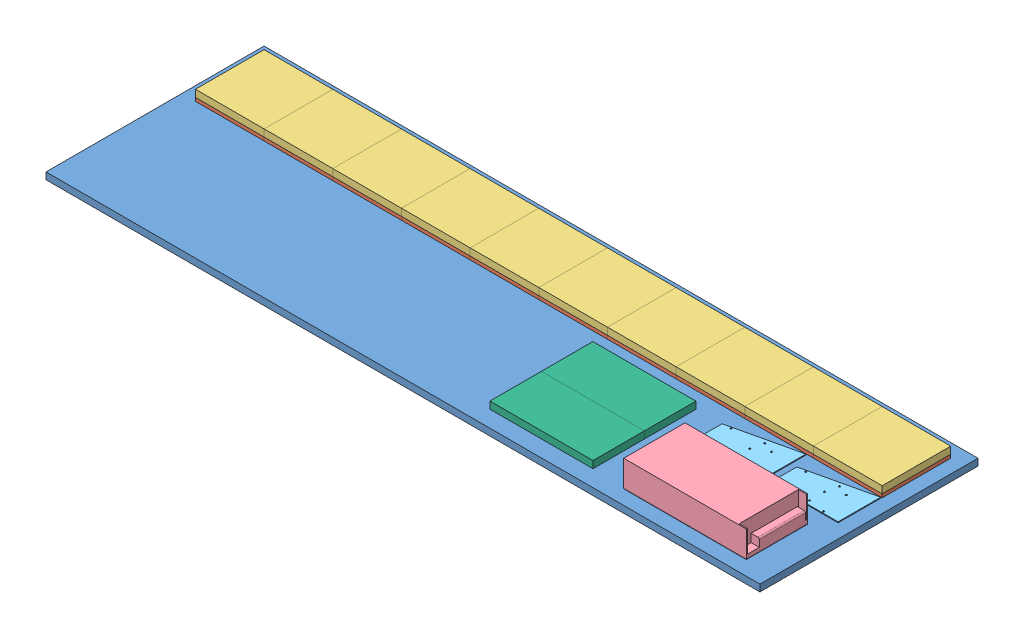
SolidWorks assembly Final_Assembly, configuration Default. Lengths in mm.
Overall size (1330.71 63.5 406.4).
28 component instances, 6 part files, 17 mates.
Components (placement in the parent):
- Back_Board-1: Back_Board [Default] at (-793.9979 16.0391 154.074) size (1330.71 12.7 406.4)
- 5_Display_Assembly-3: 5_Display_Assembly [Default] at (-36.1956 19.8584 -169.8312) size (639.95 19.53 127.84)
  - MDF-1: MDF [Default] at (-92.4493 8.8807 70.7434) size (127.99 6.35 127.84)
  - 32x32_Display-1: 32x32_Display [Default] at (-92.4493 15.2307 70.7434) size (127.99 16.87 127.84)
  - MDF-2: MDF [Default] at (35.5413 8.8807 70.7434) size (127.99 6.35 127.84)
  - MDF-3: MDF [Default] at (163.5319 8.8807 70.7434) size (127.99 6.35 127.84)
  - MDF-4: MDF [Default] at (291.5225 8.8807 70.7434) size (127.99 6.35 127.84)
  - MDF-5: MDF [Default] at (419.5131 8.8807 70.7434) size (127.99 6.35 127.84)
  - 32x32_Display-2: 32x32_Display [Default] at (35.5413 15.2307 70.7434) size (127.99 16.87 127.84)
  - 32x32_Display-3: 32x32_Display [Default] at (163.5319 15.2307 70.7434) size (127.99 16.87 127.84)
  - 32x32_Display-4: 32x32_Display [Default] at (291.5225 15.2307 70.7434) size (127.99 16.87 127.84)
  - 32x32_Display-5: 32x32_Display [Default] at (419.5131 15.2307 70.7434) size (127.99 16.87 127.84)
- 5_Display_Assembly-4: 5_Display_Assembly [Default] at (-676.1486 19.8584 -169.8312) size (639.95 19.53 127.84)
  - MDF-1: MDF [Default] at (-92.4493 8.8807 70.7434) size (127.99 6.35 127.84)
  - 32x32_Display-1: 32x32_Display [Default] at (-92.4493 15.2307 70.7434) size (127.99 16.87 127.84)
  - MDF-2: MDF [Default] at (35.5413 8.8807 70.7434) size (127.99 6.35 127.84)
  - MDF-3: MDF [Default] at (163.5319 8.8807 70.7434) size (127.99 6.35 127.84)
  - MDF-4: MDF [Default] at (291.5225 8.8807 70.7434) size (127.99 6.35 127.84)
  - MDF-5: MDF [Default] at (419.5131 8.8807 70.7434) size (127.99 6.35 127.84)
  - 32x32_Display-2: 32x32_Display [Default] at (35.5413 15.2307 70.7434) size (127.99 16.87 127.84)
  - 32x32_Display-3: 32x32_Display [Default] at (163.5319 15.2307 70.7434) size (127.99 16.87 127.84)
  - 32x32_Display-4: 32x32_Display [Default] at (291.5225 15.2307 70.7434) size (127.99 16.87 127.84)
  - 32x32_Display-5: 32x32_Display [Default] at (419.5131 15.2307 70.7434) size (127.99 16.87 127.84)
- Power_Supply-1: Power_Supply [Default] at (311.5374 28.7391 59.0862) size (228.6 50.8 114.3)
- ADK-1: ADK [Default] at (430.3777 41.4391 -15.7732) size (127 1.59 79.27)
- ADK-2: ADK [Default] at (290.9928 41.4391 -15.7732) size (127 1.59 79.27)
- 16x32_Display-1: 16x32_Display [Default] at (9.0779 35.0891 33.8227) size (192.09 16.87 95.94)
- 16x32_Display-2: 16x32_Display [Default] at (9.0779 35.0891 129.7585) size (192.09 16.87 95.94)
Mates (geometry in assembly coordinates):
- Coincident9: coincident anti-aligned: plane of Back_Board-1 through (-793.9979 28.7391 154.074) normal (0 1 0); plane of 5_Display_Assembly-4/MDF-5 through (-256.6355 28.7391 -99.0878) normal (0 -1 0)
- Coincident10: coincident anti-aligned: plane of Back_Board-1 through (-793.9979 28.7391 154.074) normal (0 1 0); plane of 5_Display_Assembly-3/MDF-1 through (-128.6449 28.7391 -99.0878) normal (0 -1 0)
- Coincident11: coincident anti-aligned: plane of 5_Display_Assembly-3/MDF-1 through (-128.6449 35.0891 -99.0878) normal (-1 0 0); plane of 5_Display_Assembly-4/MDF-5 through (-128.6449 35.0891 -99.0878) normal (1 0 0)
- Coincident12: coincident aligned: plane of 5_Display_Assembly-3/MDF-1 through (-128.6449 35.0891 -226.926) normal (0 0 -1); plane of 5_Display_Assembly-4/MDF-5 through (-256.6355 35.0891 -226.926) normal (0 0 -1)
- Distance5: distance = 25.4 mm aligned: plane of 5_Display_Assembly-4/MDF-1 through (-768.5979 35.0891 -226.926) normal (0 0 -1); plane of Back_Board-1 through (-793.9979 28.7391 -252.326) normal (0 0 -1)
- Distance6: distance = 25.4 mm aligned: plane of Back_Board-1 through (-793.9979 28.7391 154.074) normal (-1 0 0); plane of 5_Display_Assembly-4/MDF-1 through (-768.5979 35.0891 -99.0878) normal (-1 0 0)
- Parallel1: parallel aligned: plane of Back_Board-1 through (-793.9979 28.7391 154.074) normal (0 0 1); plane of ADK-2 through (256.8813 43.0266 -5.0636) normal (0 0 1)
- Distance7: distance = 12.7 mm anti-aligned: plane of ADK-2 through (290.9928 41.4391 -15.7732) normal (0 -1 0); plane of Back_Board-1 through (-793.9979 28.7391 154.074) normal (0 1 0)
- Coincident18: coincident aligned: plane of ADK-1 through (396.2663 43.0266 -5.0636) normal (0 0 1); plane of ADK-2 through (256.8813 43.0266 -5.0636) normal (0 0 1)
- Coincident19: coincident aligned: plane of ADK-1 through (430.3777 43.0266 -15.7732) normal (0 1 0); plane of ADK-2 through (290.9928 43.0266 -15.7732) normal (0 1 0)
- Coincident20: coincident anti-aligned: plane of Back_Board-1 through (-793.9979 28.7391 154.074) normal (0 1 0); plane of Power_Supply-1 through (311.5374 28.7391 59.0862) normal (0 -1 0)
- Distance8: distance = 25.4 mm aligned: plane of Power_Supply-1 through (257.3081 79.5391 128.674) normal (0 0 1); plane of Back_Board-1 through (-793.9979 28.7391 154.074) normal (0 0 1)
- Distance9: distance = 50.8 mm aligned: plane of Power_Supply-1 through (485.9081 79.5391 14.374) normal (1 0 0); plane of Back_Board-1 through (536.7081 28.7391 154.074) normal (1 0 0)
- Coincident21: coincident aligned: plane of 5_Display_Assembly-3/32x32_Display-2 through (-0.6543 48.2717 -99.0878) normal (0 1 0); plane of 16x32_Display-2 through (9.0779 48.2717 129.7585) normal (0 1 0)
- Coincident22: coincident aligned: plane of 16x32_Display-1 through (9.0779 48.2717 33.8227) normal (0 1 0); plane of 16x32_Display-2 through (9.0779 48.2717 129.7585) normal (0 1 0)
- Coincident23: coincident aligned: plane of 16x32_Display-1 through (9.0779 48.2717 33.8227) normal (-1 0 0); plane of 16x32_Display-2 through (9.0779 48.2717 129.7585) normal (-1 0 0)
- Coincident24: coincident anti-aligned: plane of 16x32_Display-1 through (9.0779 48.2717 33.8227) normal (0 0 1); plane of 16x32_Display-2 through (9.0779 48.2717 33.8227) normal (0 0 -1)
